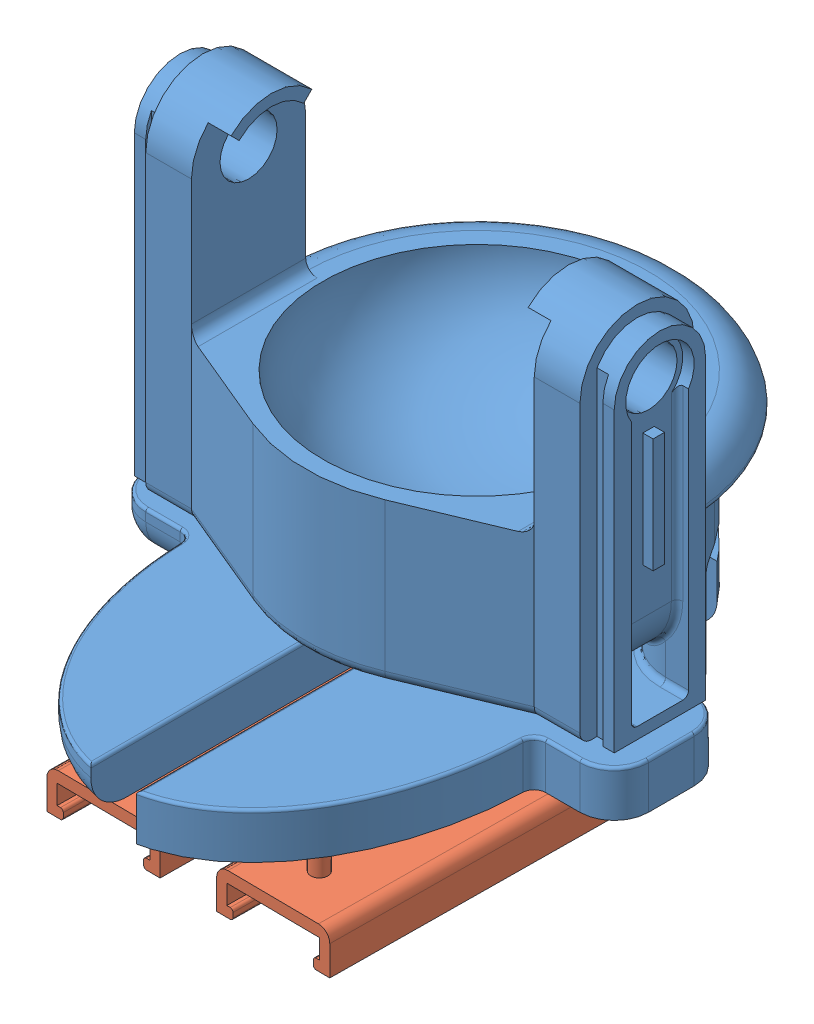
SolidWorks assembly foodwell-with endcaps, configuration Default. Lengths in mm.
Overall size (44 44.6 51.61).
3 component instances, 2 part files, 4 mates.
Components (placement in the parent):
- foodwell_all-1: foodwell_all [Default] at origin size (44 36.18 51.61)
- foodwell_endcap-1: foodwell_endcap [Default] at (-2.9921 -10 24.7562) x (-0.999952 0 -0.009754) z (0 -1 0) size (10 31 8.6)
- foodwell_endcap-2: foodwell_endcap [Default] at (12.0072 -10 24.9025) x (-0.999952 0 -0.009754) z (0 -1 0) size (10 31 8.6)
Mates (geometry in assembly coordinates):
- Coincident3: coincident aligned: plane of foodwell_endcap-1 through (-2.9921 -11 24.7562) normal (-0.009754 0 0.999952); plane of foodwell_endcap-2 through (12.0072 -11 24.9025) normal (-0.009754 0 0.999952)
- Coincident4: coincident aligned: plane of foodwell_endcap-1 through (-2.7385 -10 -1.2426) normal (0 1 0); plane of foodwell_endcap-2 through (12.2608 -10 -1.0963) normal (0 1 0)
- Distance3: distance = 5 mm anti-aligned: plane of foodwell_endcap-2 through (2.0076 -11 24.8049) normal (-0.999952 0 -0.009754); plane of foodwell_endcap-1 through (-2.9921 -11 24.7562) normal (0.999952 0 0.009754)
- Coincident9: coincident anti-aligned: plane of foodwell_all-1 through (0 -5 0) normal (0 -1 0); plane of foodwell_endcap-2 through (7.0464 -5 20.8539) normal (0 1 0)
